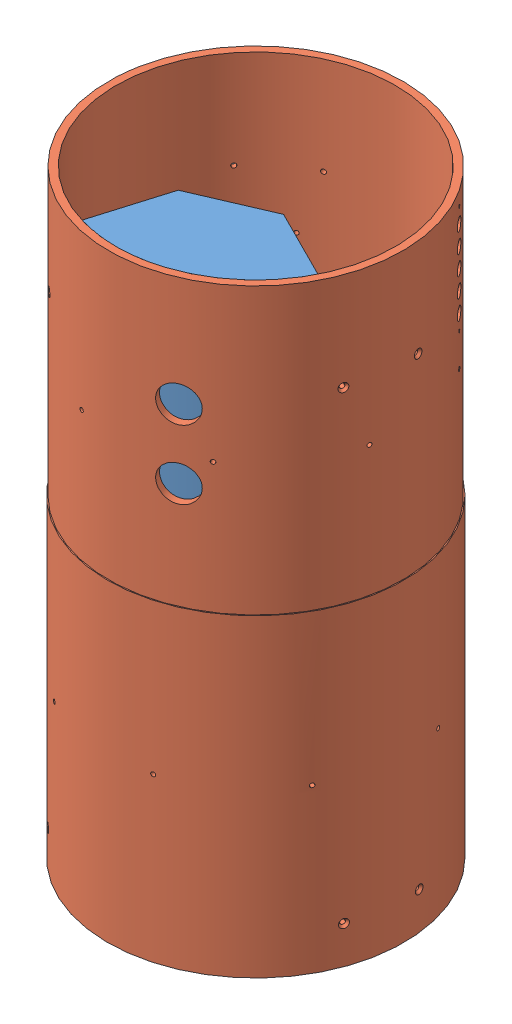
SolidWorks assembly Camera Test Assembly, configuration Default. Lengths in mm.
Overall size (216.43 393.7 216.43).
2 component instances, 2 part files, 2 mates.
Components (placement in the parent):
- Camera Test Brick-1: Camera Test Brick [Default] at origin size (108.38 153.92 73.41)
- Nose2BodyCoupler-1: Nose2BodyCoupler [Default] at (-0.0445 -239.776 -0.0107) x (-0.119236 0 0.992866) z (-0.992866 0 -0.119236) size (194.61 393.7 194.61)
Mates (geometry in assembly coordinates):
- Coincident1: coincident aligned: plane of Camera Test Brick-1 through (0 153.924 0) normal (0 1 0); circle of Nose2BodyCoupler-1
- Tangent6: tangent aligned: cylinder of Camera Test Brick-1 through (0 153.924 0) axis (0 -1 0) radius 91.821; cylinder of Nose2BodyCoupler-1 through (-0.0445 153.924 -0.0107) axis (0 -1 0) radius 91.8667
